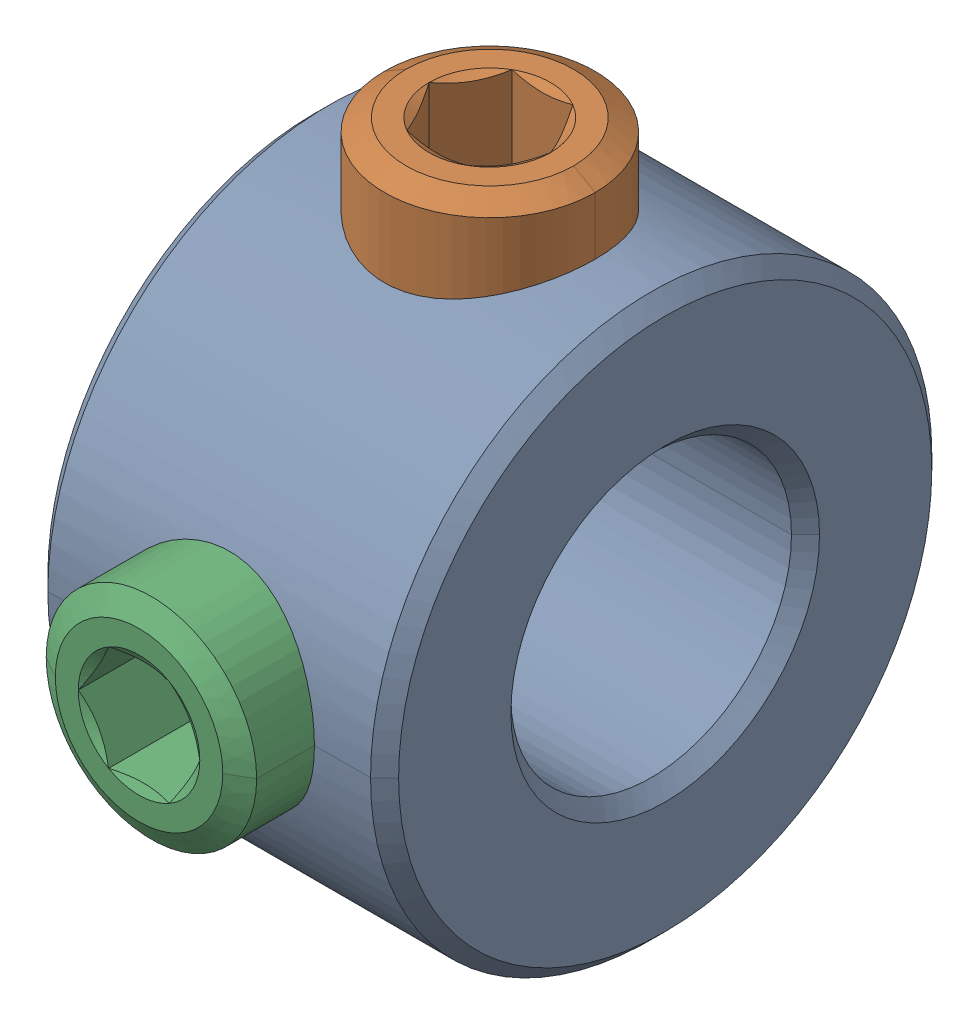
SolidWorks assembly SCCJ4_5, configuration Default. Lengths in mm.
Overall size (5 9 9).
3 component instances, 2 part files, 0 mates.
Components (placement in the parent):
- _SCCJ4_5_b_2-1: _SCCJ4_5_b_2 [Default] at origin size (5 8 8)
- _Hexagon_socket_set_screw_with_flat_point_DIN_913___M3x3_4-1: _Hexagon_socket_set_screw_with_flat_point_DIN_913___M3x3_4 [Default] at (0 5 0) x (0 -1 0) z (-1 0 0) size (3 3 3)
- _Hexagon_socket_set_screw_with_flat_point_DIN_913___M3x3_4-2: _Hexagon_socket_set_screw_with_flat_point_DIN_913___M3x3_4 [Default] at (0 0 5) x (0 0 -1) z (-1 0 0) size (3 3 3)
